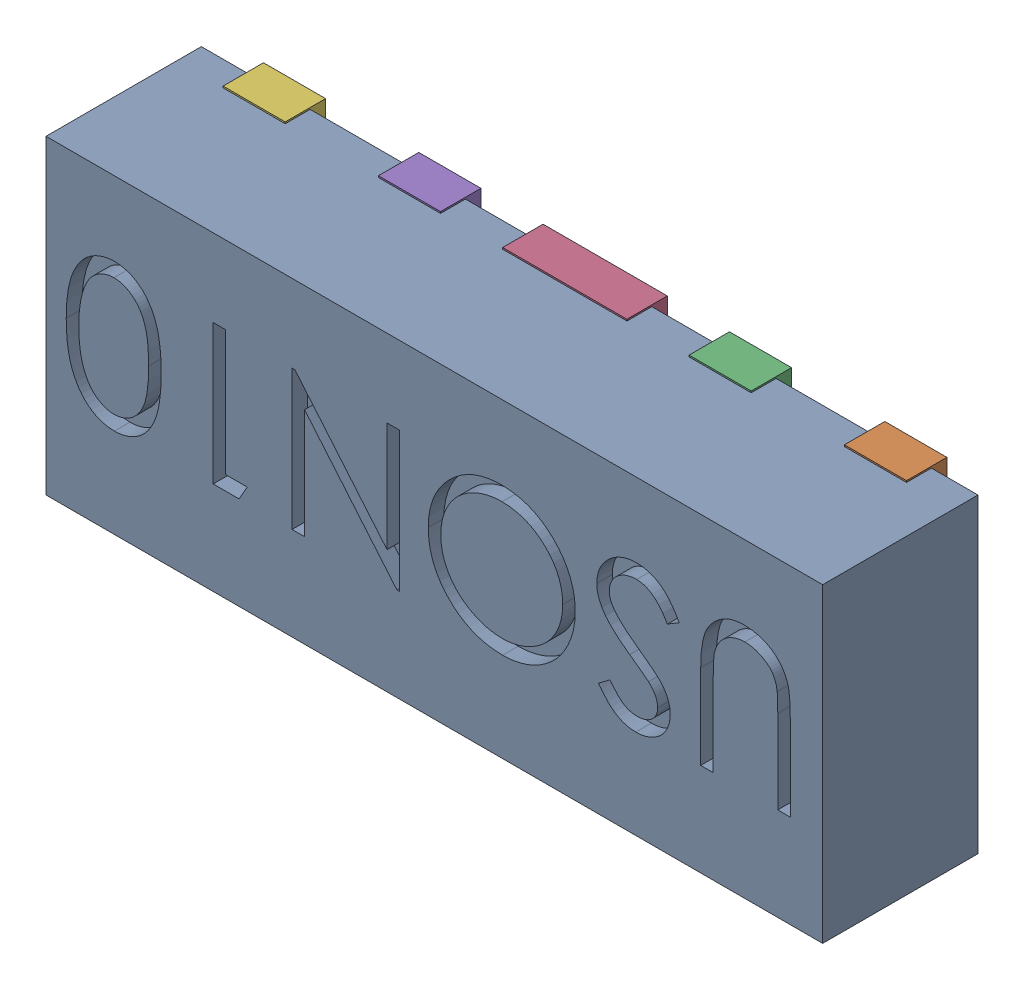
SolidWorks assembly D3, configuration Défaut. Lengths in mm.
Overall size (2.5 1.01 0.55).
12 component instances, 5 part files, 0 mates.
Components (placement in the parent):
- UDFN10-1: UDFN10 [Défaut] at (63.1497 -30.6335 -0.9099) x (-1 0 0) z (0 1 0) size (2.5 0.55 1.01)
  - User Library-UDFN10_Body-1: User Library-UDFN10_Body [Défaut] at (1.0785 0.9721 1.8983) size (2.5 0.5 1)
  - User Library-UDFN10_Pin1-1: User Library-UDFN10_Pin1 [Défaut] at (0.0785 1.0521 2.2208) x (0 0 -1) z (-1 0 0) size (0.37 0.13 0.2)
  - User Library-UDFN10_Pin2-1: User Library-UDFN10_Pin2 [Défaut] at (0.5785 1.0521 2.2208) x (0 0 1) z (1 0 0) size (0.37 0.13 0.2)
  - User Library-UDFN10_Pin4-1: User Library-UDFN10_Pin4 [Défaut] at (1.0785 0.9221 2.2208) x (0 0 1) z (-1 0 0) size (0.49 0.13 0.4)
  - User Library-UDFN10_Pin2-2: User Library-UDFN10_Pin2 [Défaut] at (1.5785 0.9221 2.2208) x (0 0 1) z (-1 0 0) size (0.37 0.13 0.2)
  - User Library-UDFN10_Pin2-3: User Library-UDFN10_Pin2 [Défaut] at (2.0785 0.9221 2.2208) x (0 0 1) z (-1 0 0) size (0.37 0.13 0.2)
  - User Library-UDFN10_Pin2-4: User Library-UDFN10_Pin2 [Défaut] at (2.0785 0.9221 1.5758) x (0 0 -1) z (1 0 0) size (0.37 0.13 0.2)
  - User Library-UDFN10_Pin2-5: User Library-UDFN10_Pin2 [Défaut] at (1.5785 0.9221 1.5758) x (0 0 -1) z (1 0 0) size (0.37 0.13 0.2)
  - User Library-UDFN10_Pin3-1: User Library-UDFN10_Pin3 [Défaut] at (1.0785 0.9221 1.5758) x (0 0 1) z (-1 0 0) size (0.37 0.13 0.4)
  - User Library-UDFN10_Pin2-6: User Library-UDFN10_Pin2 [Défaut] at (0.5785 0.9221 1.5758) x (0 0 -1) z (1 0 0) size (0.37 0.13 0.2)
  - User Library-UDFN10_Pin2-7: User Library-UDFN10_Pin2 [Défaut] at (0.0785 0.9221 1.5758) x (0 0 -1) z (1 0 0) size (0.37 0.13 0.2)
